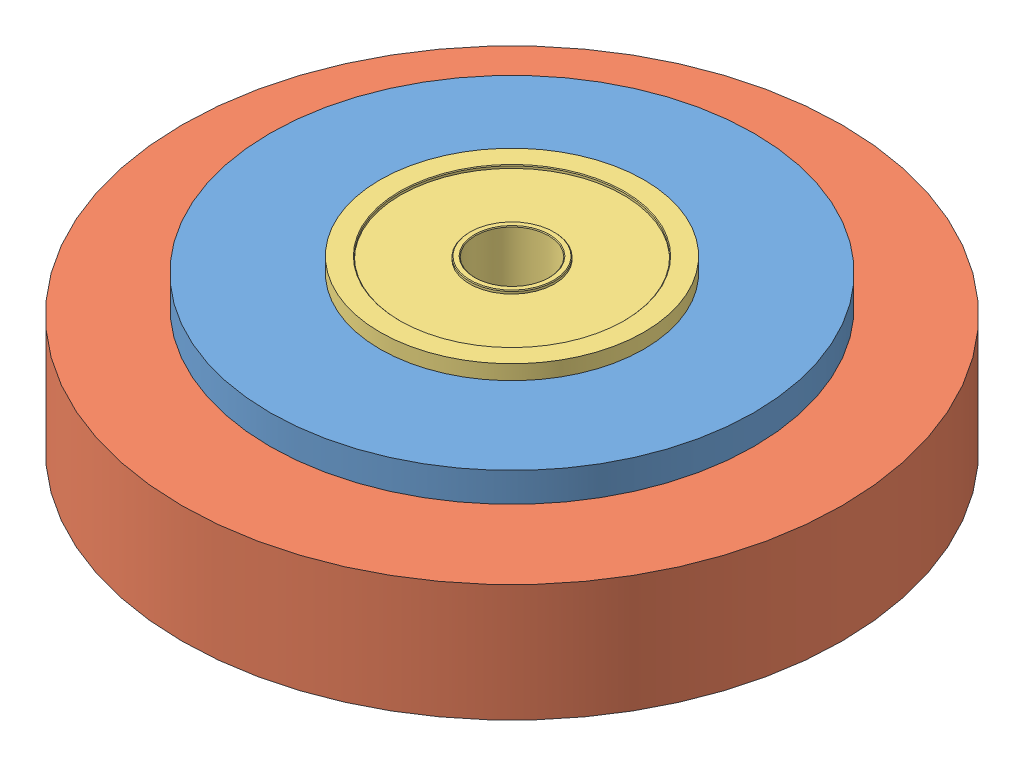
SolidWorks assembly 导向轮_轮, configuration 默认. Lengths in mm.
Overall size (45 14.5 45).
4 component instances, 3 part files, 27 mates.
Components (placement in the parent):
- 导向轮_轮毂-1: 导向轮_轮毂 [默认] at origin size (33 12.5 33)
- 导向轮_硅胶圈-1: 导向轮_硅胶圈 [默认] at (0 -0.25 0) size (45 8 45)
- 法兰轴承库-1: 法兰轴承库 [5_16_5_1] at (0 -4.75 0) x (1 0 0) z (0 1 0) size (18 18 5)
- 法兰轴承库-2: 法兰轴承库 [5_16_5_1] at (0 4.75 0) x (1 0 0) z (0 -1 0) size (18 18 5)
Mates (geometry in assembly coordinates):
- 重合1: coincident: plane of assembly through (0 0 0) normal (0 0 1); plane of 导向轮_轮毂-1 through (0 0 0) normal (0 0 1); plane of assembly
- 重合2: coincident: plane of assembly through (0 0 0) normal (0 1 0); plane of 导向轮_轮毂-1 through (0 0 0) normal (0 1 0); plane of assembly
- 重合3: coincident: plane of assembly through (0 0 0) normal (1 0 0); plane of 导向轮_轮毂-1 through (0 0 0) normal (1 0 0); plane of assembly
- 同心1: concentric: cylinder of assembly; cylinder of assembly; cylinder of 导向轮_轮毂-1 through (0 35.1394 0) axis (0 1 0) radius 13.5; cylinder of 导向轮_硅胶圈-1 through (0 3.75 0) axis (0 -1 0) radius 12.5
- 重合4: coincident: plane of assembly; plane of assembly; plane of 导向轮_轮毂-1 through (0 -4.25 0) normal (0 1 0); plane of 导向轮_硅胶圈-1 through (0 -4.25 0) normal (0 -1 0)
- 同心2: concentric: cylinder of assembly; cylinder of assembly; cylinder of 导向轮_轮毂-1 through (0 35.1394 0) axis (0 1 0) radius 7.95; cylinder of 法兰轴承库-2 through (0 2.25 0) axis (0 1 0) radius 2.5
- 重合5: coincident: plane of assembly; plane of assembly; plane of 导向轮_轮毂-1 through (0 6.25 0) normal (0 1 0); plane of 法兰轴承库-2 through (0 6.25 0) normal (0 -1 0)
- 重合6: coincident: plane of assembly; plane of assembly; plane of 导向轮_轮毂-1 through (0 -6.25 0) normal (0 -1 0); plane of 法兰轴承库-1 through (0 -6.25 0) normal (0 1 0)
- 同心3: concentric: cylinder of assembly; cylinder of assembly; cylinder of 导向轮_轮毂-1 through (0 35.1394 0) axis (0 1 0) radius 7.95; cylinder of 法兰轴承库-1 through (0 -2.25 0) axis (0 -1 0) radius 8
- 重合13: coincident: plane of assembly through (0 0 0) normal (0 0 1); plane of 导向轮_轮毂-1 through (0 0 0) normal (0 0 1); plane of assembly
- 重合14: coincident: plane of assembly through (0 0 0) normal (0 1 0); plane of 导向轮_轮毂-1 through (0 0 0) normal (0 1 0); plane of assembly
- 重合15: coincident: plane of assembly through (0 0 0) normal (1 0 0); plane of 导向轮_轮毂-1 through (0 0 0) normal (1 0 0); plane of assembly
- 同心7: concentric: cylinder of assembly; cylinder of assembly; cylinder of 导向轮_轮毂-1 through (0 35.1394 0) axis (0 1 0) radius 13.5; cylinder of 导向轮_硅胶圈-1 through (0 3.75 0) axis (0 -1 0) radius 12.5
- 重合16: coincident: plane of assembly; plane of assembly; plane of 导向轮_轮毂-1 through (0 -4.25 0) normal (0 1 0); plane of 导向轮_硅胶圈-1 through (0 -4.25 0) normal (0 -1 0)
- 同心8: concentric: cylinder of assembly; cylinder of assembly; cylinder of 导向轮_轮毂-1 through (0 35.1394 0) axis (0 1 0) radius 7.95; cylinder of 法兰轴承库-2 through (0 2.25 0) axis (0 1 0) radius 2.5
- 重合17: coincident: plane of assembly; plane of assembly; plane of 导向轮_轮毂-1 through (0 6.25 0) normal (0 1 0); plane of 法兰轴承库-2 through (0 6.25 0) normal (0 -1 0)
- 重合18: coincident: plane of assembly; plane of assembly; plane of 导向轮_轮毂-1 through (0 -6.25 0) normal (0 -1 0); plane of 法兰轴承库-1 through (0 -6.25 0) normal (0 1 0)
- 同心9: concentric: cylinder of assembly; cylinder of assembly; cylinder of 导向轮_轮毂-1 through (0 35.1394 0) axis (0 1 0) radius 7.95; cylinder of 法兰轴承库-1 through (0 -2.25 0) axis (0 -1 0) radius 8
- 重合19: coincident: plane of assembly through (0 0 0) normal (0 0 1); plane of 导向轮_轮毂-1 through (0 0 0) normal (0 0 1); plane of assembly
- 重合20: coincident: plane of assembly through (0 0 0) normal (0 1 0); plane of 导向轮_轮毂-1 through (0 0 0) normal (0 1 0); plane of assembly
- 重合21: coincident: plane of assembly through (0 0 0) normal (1 0 0); plane of 导向轮_轮毂-1 through (0 0 0) normal (1 0 0); plane of assembly
- 同心10: concentric: cylinder of assembly; cylinder of assembly; cylinder of 导向轮_轮毂-1 through (0 35.1394 0) axis (0 1 0) radius 13.5; cylinder of 导向轮_硅胶圈-1 through (0 3.75 0) axis (0 -1 0) radius 12.5
- 重合22: coincident: plane of assembly; plane of assembly; plane of 导向轮_轮毂-1 through (0 -4.25 0) normal (0 1 0); plane of 导向轮_硅胶圈-1 through (0 -4.25 0) normal (0 -1 0)
- 同心11: concentric: cylinder of assembly; cylinder of assembly; cylinder of 导向轮_轮毂-1 through (0 35.1394 0) axis (0 1 0) radius 7.95; cylinder of 法兰轴承库-2 through (0 2.25 0) axis (0 1 0) radius 2.5
- 重合23: coincident: plane of assembly; plane of assembly; plane of 导向轮_轮毂-1 through (0 6.25 0) normal (0 1 0); plane of 法兰轴承库-2 through (0 6.25 0) normal (0 -1 0)
- 重合24: coincident: plane of assembly; plane of assembly; plane of 导向轮_轮毂-1 through (0 -6.25 0) normal (0 -1 0); plane of 法兰轴承库-1 through (0 -6.25 0) normal (0 1 0)
- 同心12: concentric: cylinder of assembly; cylinder of assembly; cylinder of 导向轮_轮毂-1 through (0 35.1394 0) axis (0 1 0) radius 7.95; cylinder of 法兰轴承库-1 through (0 -2.25 0) axis (0 -1 0) radius 8
